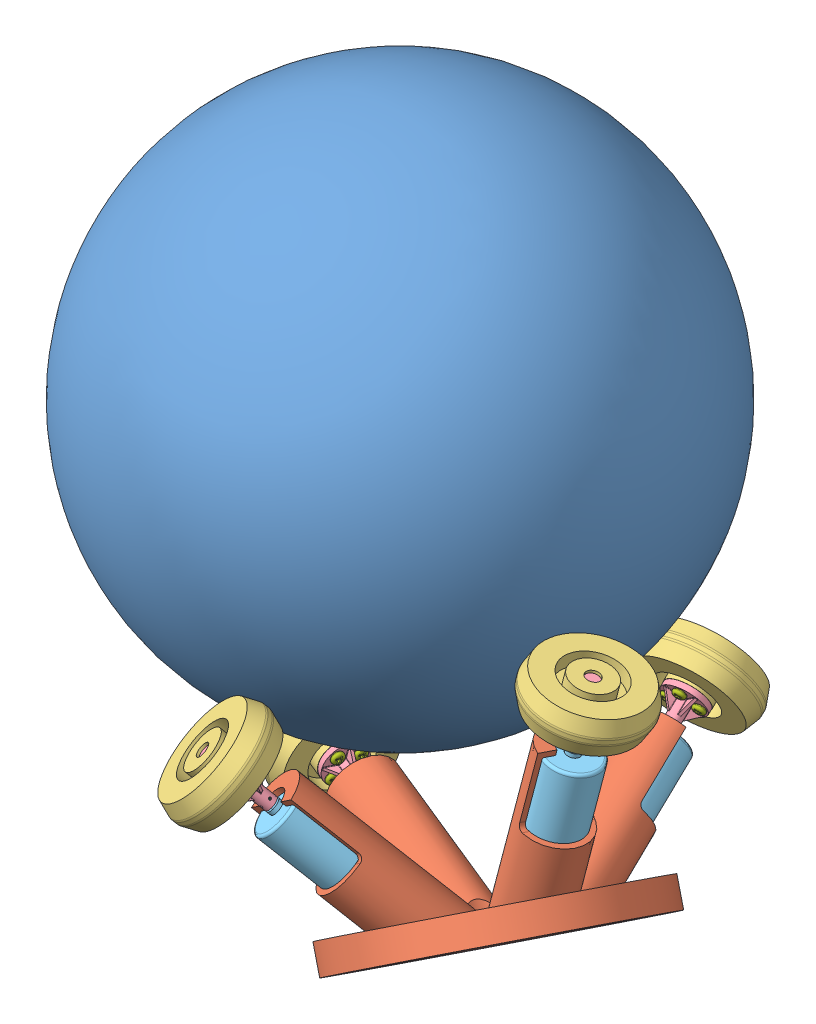
SolidWorks assembly B3_TopASM (1), configuration Default. Lengths in mm.
Overall size (343.94 359.23 303.03).
51 component instances, 7 part files, 2 mates.
Components (placement in the parent):
- Basketball-1: Basketball [Default] at (57.1301 138.7732 195.5462) size (242.57 242.57 242.57)
- FourLegASM-1: FourLegASM [Default] at (175.3269 -75.4925 176.7509) x (0.799959 0.582822 0.142771) z (-0.274013 0.143135 0.951015) size (237.13 102.02 237.13)
  - FourLegBase-1: FourLegBase [Default] at (33.0096 39.469 80.9309) size (156.3 71.93 156.3)
  - MotorWheelASM-1: MotorWheelASM [Default] at (114.1265 63.6133 80.3682) x (0 0 -1) z (0.707107 0.707107 0) size (50.8 50.8 69.16)
    - Omni_Wheel-1: Omni_Wheel [Default] at (-0.5626 28.5849 47.8869) size (50.8 50.8 16.51)
    - MotorWheelCoupler-1: MotorWheelCoupler [Default] at (-0.5626 28.5849 37.0919) size (19.05 19.05 30.48)
    - DC_Motor-1: DC_Motor [Default] at (-0.5626 28.5849 -8.9583) size (24.38 24.38 45.03)
    - 92311A050_18-8 SS CUP POINT SET SCREW-1: 92311A050_18-8 SS CUP POINT SET SCREW [92311A050] at (-2.3871 28.5849 26.9319) x (0 0 1) z (-1 0 0) size (1.76 1.55 1.71)
    - 92311A050_18-8 SS CUP POINT SET SCREW-2: 92311A050_18-8 SS CUP POINT SET SCREW [92311A050] at (-0.5626 26.7604 26.9319) x (0 0 1) z (0 -1 0) size (1.76 1.55 1.71)
    - 92311A050_18-8 SS CUP POINT SET SCREW-3: 92311A050_18-8 SS CUP POINT SET SCREW [92311A050] at (1.2619 28.5849 26.9319) x (0 0 1) z (1 0 0) size (1.76 1.55 1.71)
    - 92311A050_18-8 SS CUP POINT SET SCREW-4: 92311A050_18-8 SS CUP POINT SET SCREW [92311A050] at (-0.5626 30.4094 26.9319) x (0 0 1) z (0 1 0) size (1.76 1.55 1.71)
    - 94629A550_THREAD-CUTTING SCREW FOR SOFT PLASTICS-1: 94629A550_THREAD-CUTTING SCREW FOR SOFT PLASTICS [94629A550] at (4.0094 24.0129 37.0919) x (-0.923728 -0.383049 0) z (0 0 -1) size (5.56 5.82 14.35)
    - 94629A550_THREAD-CUTTING SCREW FOR SOFT PLASTICS-2: 94629A550_THREAD-CUTTING SCREW FOR SOFT PLASTICS [94629A550] at (4.0094 33.1569 37.0919) x (0.383049 -0.923728 0) z (0 0 -1) size (5.56 5.82 14.35)
    - 94629A550_THREAD-CUTTING SCREW FOR SOFT PLASTICS-3: 94629A550_THREAD-CUTTING SCREW FOR SOFT PLASTICS [94629A550] at (-5.1346 33.1569 37.0919) x (0.923728 0.383049 0) z (0 0 -1) size (5.56 5.82 14.35)
    - 94629A550_THREAD-CUTTING SCREW FOR SOFT PLASTICS-4: 94629A550_THREAD-CUTTING SCREW FOR SOFT PLASTICS [94629A550] at (-5.1346 24.0129 37.0919) x (-0.383049 0.923728 0) z (0 0 -1) size (5.56 5.82 14.35)
  - MotorWheelASM-2: MotorWheelASM [Default] at (33.5723 63.6133 162.0477) x (1 0 0) z (0 0.707107 0.707107) size (50.8 50.8 69.16)
    - Omni_Wheel-1: Omni_Wheel [Default] at (-0.5626 28.5849 47.8869) size (50.8 50.8 16.51)
    - MotorWheelCoupler-1: MotorWheelCoupler [Default] at (-0.5626 28.5849 37.0919) size (19.05 19.05 30.48)
    - DC_Motor-1: DC_Motor [Default] at (-0.5626 28.5849 -8.9583) size (24.38 24.38 45.03)
    - 92311A050_18-8 SS CUP POINT SET SCREW-1: 92311A050_18-8 SS CUP POINT SET SCREW [92311A050] at (-2.3871 28.5849 26.9319) x (0 0 1) z (-1 0 0) size (1.76 1.55 1.71)
    - 92311A050_18-8 SS CUP POINT SET SCREW-2: 92311A050_18-8 SS CUP POINT SET SCREW [92311A050] at (-0.5626 26.7604 26.9319) x (0 0 1) z (0 -1 0) size (1.76 1.55 1.71)
    - 92311A050_18-8 SS CUP POINT SET SCREW-3: 92311A050_18-8 SS CUP POINT SET SCREW [92311A050] at (1.2619 28.5849 26.9319) x (0 0 1) z (1 0 0) size (1.76 1.55 1.71)
    - 92311A050_18-8 SS CUP POINT SET SCREW-4: 92311A050_18-8 SS CUP POINT SET SCREW [92311A050] at (-0.5626 30.4094 26.9319) x (0 0 1) z (0 1 0) size (1.76 1.55 1.71)
    - 94629A550_THREAD-CUTTING SCREW FOR SOFT PLASTICS-1: 94629A550_THREAD-CUTTING SCREW FOR SOFT PLASTICS [94629A550] at (4.0094 24.0129 37.0919) x (-0.923728 -0.383049 0) z (0 0 -1) size (5.56 5.82 14.35)
    - 94629A550_THREAD-CUTTING SCREW FOR SOFT PLASTICS-2: 94629A550_THREAD-CUTTING SCREW FOR SOFT PLASTICS [94629A550] at (4.0094 33.1569 37.0919) x (0.383049 -0.923728 0) z (0 0 -1) size (5.56 5.82 14.35)
    - 94629A550_THREAD-CUTTING SCREW FOR SOFT PLASTICS-3: 94629A550_THREAD-CUTTING SCREW FOR SOFT PLASTICS [94629A550] at (-5.1346 33.1569 37.0919) x (0.923728 0.383049 0) z (0 0 -1) size (5.56 5.82 14.35)
    - 94629A550_THREAD-CUTTING SCREW FOR SOFT PLASTICS-4: 94629A550_THREAD-CUTTING SCREW FOR SOFT PLASTICS [94629A550] at (-5.1346 24.0129 37.0919) x (-0.383049 0.923728 0) z (0 0 -1) size (5.56 5.82 14.35)
  - MotorWheelASM-3: MotorWheelASM [Default] at (-48.1072 63.6133 81.4935) x (0 0 1) z (-0.707107 0.707107 0) size (50.8 50.8 69.16)
    - Omni_Wheel-1: Omni_Wheel [Default] at (-0.5626 28.5849 47.8869) size (50.8 50.8 16.51)
    - MotorWheelCoupler-1: MotorWheelCoupler [Default] at (-0.5626 28.5849 37.0919) size (19.05 19.05 30.48)
    - DC_Motor-1: DC_Motor [Default] at (-0.5626 28.5849 -8.9583) size (24.38 24.38 45.03)
    - 92311A050_18-8 SS CUP POINT SET SCREW-1: 92311A050_18-8 SS CUP POINT SET SCREW [92311A050] at (-2.3871 28.5849 26.9319) x (0 0 1) z (-1 0 0) size (1.76 1.55 1.71)
    - 92311A050_18-8 SS CUP POINT SET SCREW-2: 92311A050_18-8 SS CUP POINT SET SCREW [92311A050] at (-0.5626 26.7604 26.9319) x (0 0 1) z (0 -1 0) size (1.76 1.55 1.71)
    - 92311A050_18-8 SS CUP POINT SET SCREW-3: 92311A050_18-8 SS CUP POINT SET SCREW [92311A050] at (1.2619 28.5849 26.9319) x (0 0 1) z (1 0 0) size (1.76 1.55 1.71)
    - 92311A050_18-8 SS CUP POINT SET SCREW-4: 92311A050_18-8 SS CUP POINT SET SCREW [92311A050] at (-0.5626 30.4094 26.9319) x (0 0 1) z (0 1 0) size (1.76 1.55 1.71)
    - 94629A550_THREAD-CUTTING SCREW FOR SOFT PLASTICS-1: 94629A550_THREAD-CUTTING SCREW FOR SOFT PLASTICS [94629A550] at (4.0094 24.0129 37.0919) x (-0.923728 -0.383049 0) z (0 0 -1) size (5.56 5.82 14.35)
    - 94629A550_THREAD-CUTTING SCREW FOR SOFT PLASTICS-2: 94629A550_THREAD-CUTTING SCREW FOR SOFT PLASTICS [94629A550] at (4.0094 33.1569 37.0919) x (0.383049 -0.923728 0) z (0 0 -1) size (5.56 5.82 14.35)
    - 94629A550_THREAD-CUTTING SCREW FOR SOFT PLASTICS-3: 94629A550_THREAD-CUTTING SCREW FOR SOFT PLASTICS [94629A550] at (-5.1346 33.1569 37.0919) x (0.923728 0.383049 0) z (0 0 -1) size (5.56 5.82 14.35)
    - 94629A550_THREAD-CUTTING SCREW FOR SOFT PLASTICS-4: 94629A550_THREAD-CUTTING SCREW FOR SOFT PLASTICS [94629A550] at (-5.1346 24.0129 37.0919) x (-0.383049 0.923728 0) z (0 0 -1) size (5.56 5.82 14.35)
  - MotorWheelASM-4: MotorWheelASM [Default] at (32.447 63.6133 -0.186) x (-1 0 0) z (0 0.707107 -0.707107) size (50.8 50.8 69.16)
    - Omni_Wheel-1: Omni_Wheel [Default] at (-0.5626 28.5849 47.8869) size (50.8 50.8 16.51)
    - MotorWheelCoupler-1: MotorWheelCoupler [Default] at (-0.5626 28.5849 37.0919) size (19.05 19.05 30.48)
    - DC_Motor-1: DC_Motor [Default] at (-0.5626 28.5849 -8.9583) size (24.38 24.38 45.03)
    - 92311A050_18-8 SS CUP POINT SET SCREW-1: 92311A050_18-8 SS CUP POINT SET SCREW [92311A050] at (-2.3871 28.5849 26.9319) x (0 0 1) z (-1 0 0) size (1.76 1.55 1.71)
    - 92311A050_18-8 SS CUP POINT SET SCREW-2: 92311A050_18-8 SS CUP POINT SET SCREW [92311A050] at (-0.5626 26.7604 26.9319) x (0 0 1) z (0 -1 0) size (1.76 1.55 1.71)
    - 92311A050_18-8 SS CUP POINT SET SCREW-3: 92311A050_18-8 SS CUP POINT SET SCREW [92311A050] at (1.2619 28.5849 26.9319) x (0 0 1) z (1 0 0) size (1.76 1.55 1.71)
    - 92311A050_18-8 SS CUP POINT SET SCREW-4: 92311A050_18-8 SS CUP POINT SET SCREW [92311A050] at (-0.5626 30.4094 26.9319) x (0 0 1) z (0 1 0) size (1.76 1.55 1.71)
    - 94629A550_THREAD-CUTTING SCREW FOR SOFT PLASTICS-1: 94629A550_THREAD-CUTTING SCREW FOR SOFT PLASTICS [94629A550] at (4.0094 24.0129 37.0919) x (-0.923728 -0.383049 0) z (0 0 -1) size (5.56 5.82 14.35)
    - 94629A550_THREAD-CUTTING SCREW FOR SOFT PLASTICS-2: 94629A550_THREAD-CUTTING SCREW FOR SOFT PLASTICS [94629A550] at (4.0094 33.1569 37.0919) x (0.383049 -0.923728 0) z (0 0 -1) size (5.56 5.82 14.35)
    - 94629A550_THREAD-CUTTING SCREW FOR SOFT PLASTICS-3: 94629A550_THREAD-CUTTING SCREW FOR SOFT PLASTICS [94629A550] at (-5.1346 33.1569 37.0919) x (0.923728 0.383049 0) z (0 0 -1) size (5.56 5.82 14.35)
    - 94629A550_THREAD-CUTTING SCREW FOR SOFT PLASTICS-4: 94629A550_THREAD-CUTTING SCREW FOR SOFT PLASTICS [94629A550] at (-5.1346 24.0129 37.0919) x (-0.383049 0.923728 0) z (0 0 -1) size (5.56 5.82 14.35)
Mates (geometry in assembly coordinates):
- Concentric4: concentric: sphere of Basketball-1; cylinder of FourLegASM-1/FourLegBase-1 through (151.7074 -2.9401 244.1253) axis (0.533837 -0.799894 0.274203) radius 63.5
- Distance2: distance = 55.88 mm anti-aligned: plane of FourLegASM-1/FourLegBase-1 through (151.7074 -2.9401 244.1253) normal (-0.533837 0.799894 -0.274203); sphere of Basketball-1
